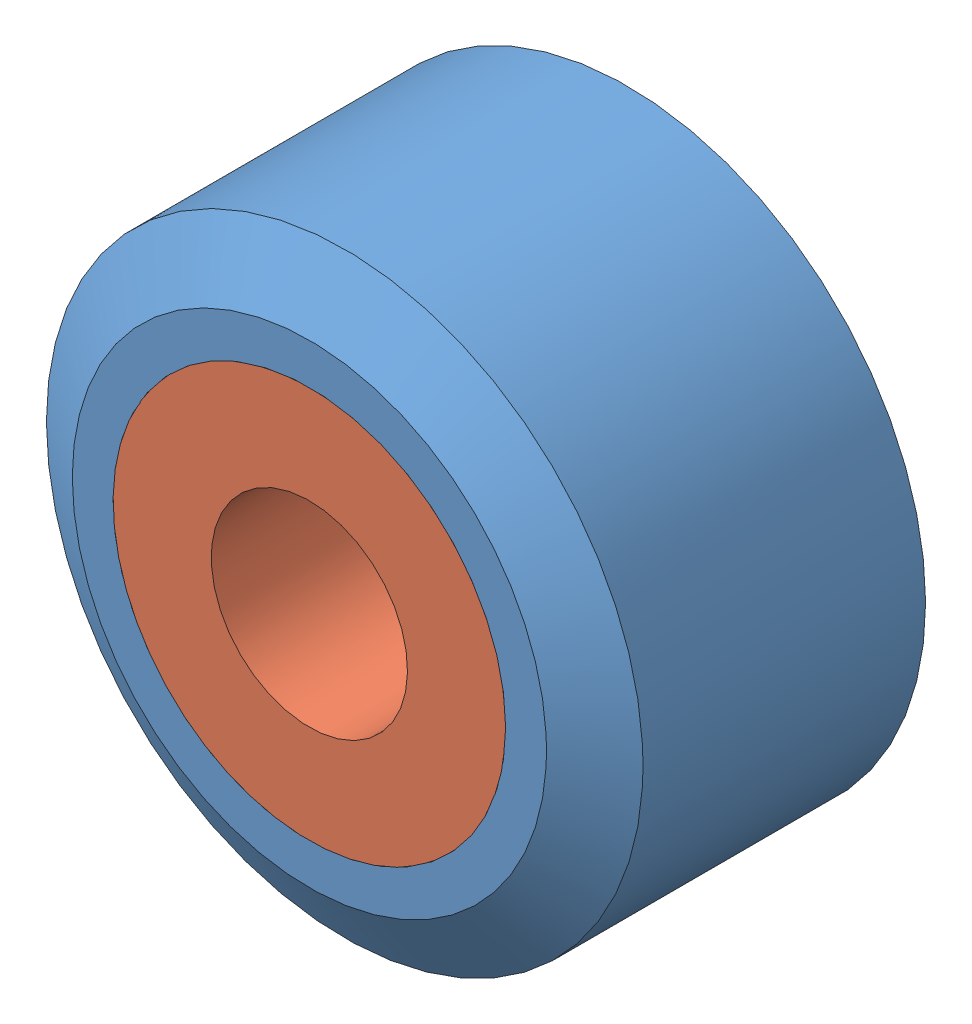
SolidWorks assembly RoueVAssemblage1, configuration Défaut. Lengths in mm.
Overall size (15.2 15.2 9).
2 component instances, 2 part files, 2 mates.
Components (placement in the parent):
- RoueV1-1: RoueV1 [Défaut] at (-2.4006 1.3504 10.7) size (15.2 15.2 9)
- RoueV2-1: RoueV2 [Défaut] at (-2.4006 1.3504 10.7) x (0.999854 -0.017094 0) z (0 0 1) size (10 10 9)
Mates (geometry in assembly coordinates):
- Coaxiale1: concentric: cylinder of RoueV1-1 through (-2.4006 1.3504 19.7) axis (0 0 -1) radius 5; cylinder of RoueV2-1 through (-2.4006 1.3504 29.6926) axis (0 0 -1) radius 5
- Coïncidente2: coincident: circle of RoueV1-1; circle of RoueV2-1
